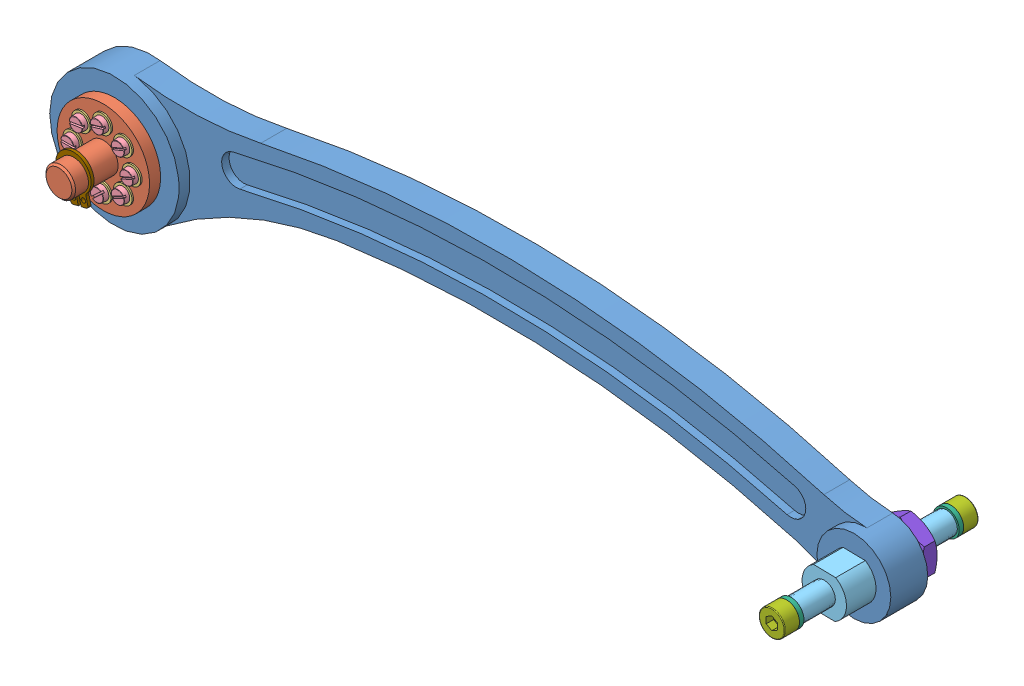
SolidWorks assembly LINK1_SUBASSEMBLY, configuration Default. Lengths in mm.
Overall size (227.5 42.75 52.4).
25 component instances, 9 part files, 49 mates.
Components (placement in the parent):
- link1-1: link1 [Default] at (9.2563 118.8073 156.0715) size (227.5 42.75 10)
- horn-1: horn [Default] at (9.2563 118.8073 166.0715) size (25 25 15)
- plain washer (type a)_is-1: plain washer (type a)_is [IS 2016 A- 2.4] at (3.5994 113.1504 169.4715) x (1 0 0) z (0 -1 0) size (5 0.4 5)
- plain washer (type a)_is-2: plain washer (type a)_is [IS 2016 A- 2.4] at (1.2563 118.8073 169.4715) x (0.987351 0.158553 0) z (0.158553 -0.987351 0) size (5 0.4 5)
- plain washer (type a)_is-4: plain washer (type a)_is [IS 2016 A- 2.4] at (3.5994 124.4641 169.4715) x (0.044015 -0.999031 0) z (-0.999031 -0.044015 0) size (5 0.4 5)
- plain washer (type a)_is-6: plain washer (type a)_is [IS 2016 A- 2.4] at (9.2563 126.8073 169.4715) x (-0.130134 -0.991496 0) z (-0.991496 0.130134 0) size (5 0.4 5)
- plain washer (type a)_is-10: plain washer (type a)_is [IS 2016 A- 2.4] at (14.9131 113.1504 169.4715) x (-0.300328 -0.953836 0) z (-0.953836 0.300328 0) size (5 0.4 5)
- plain washer (type a)_is-12: plain washer (type a)_is [IS 2016 A- 2.4] at (17.2563 118.8073 169.4715) x (-0.461398 -0.887193 0) z (-0.887193 0.461398 0) size (5 0.4 5)
- plain washer (type a)_is-14: plain washer (type a)_is [IS 2016 A- 2.4] at (14.9131 124.4641 169.4715) x (-0.608447 -0.793594 0) z (-0.793594 0.608447 0) size (5 0.4 5)
- plain washer (type a)_is-16: plain washer (type a)_is [IS 2016 A- 2.4] at (9.2563 110.8073 169.4715) x (-0.73701 -0.675882 0) z (-0.675882 0.73701 0) size (5 0.4 5)
- slotted cheese head_is-1: slotted cheese head_is [IS 1336 - M2 x 16 -- 16N] at (1.2563 118.8073 170.8715) x (0 0 -1) z (1 0 0) size (17.4 3.8 3.8)
- slotted cheese head_is-2: slotted cheese head_is [IS 1336 - M2 x 16 -- 16N] at (3.5994 124.4641 170.8715) x (0 0 -1) z (0.987351 0.158553 0) size (17.4 3.8 3.8)
- slotted cheese head_is-4: slotted cheese head_is [IS 1336 - M2 x 16 -- 16N] at (9.2563 126.8073 170.8715) x (0 0 -1) z (0.959125 0.282984 0) size (17.4 3.8 3.8)
- slotted cheese head_is-6: slotted cheese head_is [IS 1336 - M2 x 16 -- 16N] at (14.9131 124.4641 170.8715) x (0 0 -1) z (0.928571 0.371154 0) size (17.4 3.8 3.8)
- slotted cheese head_is-8: slotted cheese head_is [IS 1336 - M2 x 16 -- 16N] at (3.5994 113.1504 170.8715) x (0 0 -1) z (0.906989 0.421154 0) size (17.4 3.8 3.8)
- slotted cheese head_is-10: slotted cheese head_is [IS 1336 - M2 x 16 -- 16N] at (14.9131 113.1504 170.8715) x (0 0 -1) z (0.902849 0.429957 0) size (17.4 3.8 3.8)
- slotted cheese head_is-12: slotted cheese head_is [IS 1336 - M2 x 16 -- 16N] at (17.2563 118.8073 170.8715) x (0 0 -1) z (0.919615 0.39282 0) size (17.4 3.8 3.8)
- slotted cheese head_is-14: slotted cheese head_is [IS 1336 - M2 x 16 -- 16N] at (9.2563 110.8073 170.8715) x (0 0 -1) z (-0.73701 -0.675882 0) size (17.4 3.8 3.8)
- custom_pin-1: custom_pin [Default] at (209.2558 119.2312 150.0715) size (12 10.5 42)
- spring lock washer 6735_is-1: spring lock washer 6735_is [IS 6735- 4] at (209.2558 119.2312 183.0715) x (1 0 0) z (0 -1 0) size (7 1.23 7)
- spring lock washer 6735_is-2: spring lock washer 6735_is [IS 6735- 4] at (209.2558 119.2312 141.0715) x (-0.173648 0.984808 0) z (-0.984808 -0.173648 0) size (7 1.23 7)
- socket head cap screw_is-1: socket head cap screw_is [IS 2269 - M4 x 10-N] at (209.2558 119.2312 188.2715) x (0 0 -1) z (1 0 0) size (14 7 7)
- socket head cap screw_is-2: socket head cap screw_is [IS 2269 - M4 x 10-N] at (209.2558 119.2312 135.8715) x (0 0 1) z (-0.189245 -0.98193 0) size (14 7 7)
- hexagon thin nut (ch)_is-1: hexagon thin nut (ch)_is [IS 1364-4 - M8-N] at (209.2558 119.2312 154.0715) size (13 15.01 4)
- (normal) external_is-1: (normal) external_is [IS 3075 NE- 8] at (9.2563 118.8073 176.2715) x (0.971623 0.236536 0) z (0 0 1) size (9.57 12.08 0.8)
Mates (geometry in assembly coordinates):
- Concentric1: concentric anti-aligned: cylinder of link1-1 through (9.2563 126.8073 166.0715) axis (0 0 1) radius 1.1; cylinder of horn-1 through (9.2563 126.8073 169.0715) axis (0 0 -1) radius 1.1
- Concentric2: concentric aligned: cylinder of link1-1 through (9.2563 118.8073 166.0715) axis (0 0 -1) radius 5; cylinder of horn-1 through (9.2563 118.8073 181.0715) axis (0 0 -1) radius 4.05
- Coincident1: coincident anti-aligned: plane of link1-1 through (159.5579 -23.356 166.0715) normal (0 0 1); plane of horn-1 through (9.2563 118.8073 166.0715) normal (0 0 -1)
- Concentric8: concentric anti-aligned: cylinder of horn-1 through (3.5994 113.1504 169.0715) axis (0 0 -1) radius 1.1; cylinder of plain washer (type a)_is-1 through (3.5994 113.1504 169.4715) axis (0 0 1) radius 1.2
- Coincident5: coincident anti-aligned: plane of horn-1 through (9.2563 118.8073 169.0715) normal (0 0 1); plane of plain washer (type a)_is-1 through (4.7994 113.1504 169.0715) normal (0 0 -1)
- Concentric9: concentric anti-aligned: cylinder of horn-1 through (1.2563 118.8073 169.0715) axis (0 0 -1) radius 1.1; cylinder of plain washer (type a)_is-2 through (1.2563 118.8073 169.4715) axis (0 0 1) radius 1.2
- Coincident6: coincident anti-aligned: plane of horn-1 through (9.2563 118.8073 169.0715) normal (0 0 1); plane of plain washer (type a)_is-2 through (2.4411 118.9976 169.0715) normal (0 0 -1)
- Concentric10: concentric aligned: cylinder of link1-1 through (3.5994 124.4641 166.0715) axis (0 0 1) radius 1.1; cylinder of plain washer (type a)_is-4 through (3.5994 124.4641 169.4715) axis (0 0 1) radius 1.2
- Coincident7: coincident anti-aligned: plane of horn-1 through (9.2563 118.8073 169.0715) normal (0 0 1); plane of plain washer (type a)_is-4 through (3.6522 123.2653 169.0715) normal (0 0 -1)
- Concentric11: concentric aligned: cylinder of link1-1 through (9.2563 126.8073 166.0715) axis (0 0 1) radius 1.1; cylinder of plain washer (type a)_is-6 through (9.2563 126.8073 169.4715) axis (0 0 1) radius 1.2
- Coincident8: coincident anti-aligned: plane of horn-1 through (9.2563 118.8073 169.0715) normal (0 0 1); plane of plain washer (type a)_is-6 through (9.1001 125.6175 169.0715) normal (0 0 -1)
- Concentric12: concentric aligned: cylinder of link1-1 through (14.9131 113.1504 166.0715) axis (0 0 1) radius 1.1; cylinder of plain washer (type a)_is-10 through (14.9131 113.1504 169.4715) axis (0 0 1) radius 1.2
- Coincident9: coincident anti-aligned: plane of horn-1 through (9.2563 118.8073 169.0715) normal (0 0 1); plane of plain washer (type a)_is-10 through (14.5527 112.0058 169.0715) normal (0 0 -1)
- Concentric13: concentric aligned: cylinder of link1-1 through (17.2563 118.8073 166.0715) axis (0 0 1) radius 1.1; cylinder of plain washer (type a)_is-12 through (17.2563 118.8073 169.4715) axis (0 0 1) radius 1.2
- Coincident10: coincident anti-aligned: plane of horn-1 through (9.2563 118.8073 169.0715) normal (0 0 1); plane of plain washer (type a)_is-12 through (16.7026 117.7427 169.0715) normal (0 0 -1)
- Concentric14: concentric aligned: cylinder of link1-1 through (14.9131 124.4641 166.0715) axis (0 0 1) radius 1.1; cylinder of plain washer (type a)_is-14 through (14.9131 124.4641 169.4715) axis (0 0 1) radius 1.2
- Coincident11: coincident anti-aligned: plane of horn-1 through (9.2563 118.8073 169.0715) normal (0 0 1); plane of plain washer (type a)_is-14 through (14.183 123.5118 169.0715) normal (0 0 -1)
- Concentric15: concentric aligned: cylinder of link1-1 through (9.2563 110.8073 166.0715) axis (0 0 1) radius 1.1; cylinder of plain washer (type a)_is-16 through (9.2563 110.8073 169.4715) axis (0 0 1) radius 1.2
- Coincident12: coincident anti-aligned: plane of horn-1 through (9.2563 118.8073 169.0715) normal (0 0 1); plane of plain washer (type a)_is-16 through (8.3719 109.9962 169.0715) normal (0 0 -1)
- Concentric16: concentric anti-aligned: cylinder of horn-1 through (1.2563 118.8073 169.0715) axis (0 0 -1) radius 1.1; cylinder of slotted cheese head_is-1 through (1.2563 118.8073 170.8715) axis (0 0 1) radius 1
- Coincident13: coincident anti-aligned: plane of plain washer (type a)_is-2 through (2.4411 118.9976 169.4715) normal (0 0 1); plane of slotted cheese head_is-1 through (1.2563 120.7073 169.4715) normal (0 0 -1)
- Concentric17: concentric anti-aligned: cylinder of horn-1 through (3.5994 124.4641 169.0715) axis (0 0 -1) radius 1.1; cylinder of slotted cheese head_is-2 through (3.5994 124.4641 170.8715) axis (0 0 1) radius 1
- Coincident14: coincident anti-aligned: plane of plain washer (type a)_is-4 through (3.6522 123.2653 169.4715) normal (0 0 1); plane of slotted cheese head_is-2 through (3.2982 126.3401 169.4715) normal (0 0 -1)
- Concentric18: concentric anti-aligned: cylinder of horn-1 through (9.2563 126.8073 169.0715) axis (0 0 -1) radius 1.1; cylinder of slotted cheese head_is-4 through (9.2563 126.8073 170.8715) axis (0 0 1) radius 1
- Coincident15: coincident anti-aligned: plane of plain washer (type a)_is-6 through (9.1001 125.6175 169.4715) normal (0 0 1); plane of slotted cheese head_is-4 through (8.7186 128.6296 169.4715) normal (0 0 -1)
- Concentric19: concentric anti-aligned: cylinder of horn-1 through (14.9131 124.4641 169.0715) axis (0 0 -1) radius 1.1; cylinder of slotted cheese head_is-6 through (14.9131 124.4641 170.8715) axis (0 0 1) radius 1
- Coincident16: coincident anti-aligned: plane of plain washer (type a)_is-14 through (14.183 123.5118 169.4715) normal (0 0 1); plane of slotted cheese head_is-6 through (14.2079 126.2284 169.4715) normal (0 0 -1)
- Concentric20: concentric anti-aligned: cylinder of horn-1 through (3.5994 113.1504 169.0715) axis (0 0 -1) radius 1.1; cylinder of slotted cheese head_is-8 through (3.5994 113.1504 170.8715) axis (0 0 1) radius 1
- Coincident17: coincident anti-aligned: plane of plain washer (type a)_is-1 through (4.7994 113.1504 169.4715) normal (0 0 1); plane of slotted cheese head_is-8 through (2.7992 114.8737 169.4715) normal (0 0 -1)
- Concentric21: concentric anti-aligned: cylinder of horn-1 through (14.9131 113.1504 169.0715) axis (0 0 -1) radius 1.1; cylinder of slotted cheese head_is-10 through (14.9131 113.1504 170.8715) axis (0 0 1) radius 1
- Coincident18: coincident anti-aligned: plane of plain washer (type a)_is-10 through (14.5527 112.0058 169.4715) normal (0 0 1); plane of slotted cheese head_is-10 through (14.0962 114.8658 169.4715) normal (0 0 -1)
- Concentric22: concentric anti-aligned: cylinder of horn-1 through (17.2563 118.8073 169.0715) axis (0 0 -1) radius 1.1; cylinder of slotted cheese head_is-12 through (17.2563 118.8073 170.8715) axis (0 0 1) radius 1
- Coincident19: coincident anti-aligned: plane of plain washer (type a)_is-12 through (16.7026 117.7427 169.4715) normal (0 0 1); plane of slotted cheese head_is-12 through (16.5099 120.5546 169.4715) normal (0 0 -1)
- Concentric23: concentric aligned: cylinder of link1-1 through (9.2563 110.8073 166.0715) axis (0 0 1) radius 1.1; cylinder of slotted cheese head_is-14 through (9.2563 110.8073 170.8715) axis (0 0 1) radius 1
- Coincident20: coincident anti-aligned: plane of plain washer (type a)_is-16 through (8.3719 109.9962 169.4715) normal (0 0 1); plane of slotted cheese head_is-14 through (10.5405 109.407 169.4715) normal (0 0 -1)
- Concentric24: concentric aligned: cylinder of link1-1 through (209.2558 119.2312 166.0715) axis (0 0 -1) radius 4; cylinder of custom_pin-1 through (209.2558 119.2312 166.0715) axis (0 0 -1) radius 4
- Coincident21: coincident anti-aligned: plane of link1-1 through (159.5579 -23.356 166.0715) normal (0 0 1); plane of custom_pin-1 through (209.2558 119.2312 166.0715) normal (0 0 -1)
- Concentric25: concentric anti-aligned: cylinder of custom_pin-1 through (209.2558 119.2312 183.0715) axis (0 0 1) radius 1.65; cylinder of spring lock washer 6735_is-1 through (209.2558 119.2312 184.2715) axis (0 0 -1) radius 2.2
- Coincident22: coincident anti-aligned: plane of custom_pin-1 through (209.2558 119.2312 183.0715) normal (0 0 1); plane of spring lock washer 6735_is-1 through (209.2558 119.2312 183.0715) normal (0 0 -1)
- Concentric26: concentric anti-aligned: cylinder of custom_pin-1 through (209.2558 119.2312 141.0715) axis (0 0 -1) radius 1.65; cylinder of spring lock washer 6735_is-2 through (209.2558 119.2312 139.8715) axis (0 0 1) radius 2.2
- Coincident23: coincident anti-aligned: plane of custom_pin-1 through (209.2558 119.2312 141.0715) normal (0 0 -1); plane of spring lock washer 6735_is-2 through (209.2558 119.2312 141.0715) normal (0 0 1)
- Concentric27: concentric anti-aligned: cylinder of custom_pin-1 through (209.2558 119.2312 141.0715) axis (0 0 -1) radius 1.65; cylinder of socket head cap screw_is-1 through (209.2558 119.2312 188.2715) axis (0 0 1) radius 2
- Coincident24: coincident anti-aligned: plane of spring lock washer 6735_is-1 through (209.2558 119.2312 184.2715) normal (0 0 1); plane of socket head cap screw_is-1 through (209.2558 122.7312 184.2715) normal (0 0 -1)
- Concentric28: concentric anti-aligned: cylinder of custom_pin-1 through (209.2558 119.2312 141.0715) axis (0 0 1) radius 3; cylinder of socket head cap screw_is-2 through (209.2558 119.2312 135.8715) axis (0 0 -1) radius 2
- Coincident25: coincident anti-aligned: plane of spring lock washer 6735_is-2 through (209.2558 119.2312 139.8715) normal (0 0 -1); plane of socket head cap screw_is-2 through (205.8191 119.8936 139.8715) normal (0 0 1)
- Concentric29: concentric aligned: cylinder of custom_pin-1 through (209.2558 119.2312 141.0715) axis (0 0 1) radius 3; cylinder of hexagon thin nut (ch)_is-1 through (209.2558 119.2312 150.0715) axis (0 0 1) radius 3.4
- Coincident26: coincident aligned: plane of custom_pin-1 through (209.2558 119.2312 150.0715) normal (0 0 -1); plane of hexagon thin nut (ch)_is-1 through (209.2558 126.7368 150.0715) normal (0 0 -1)
- Concentric31: concentric anti-aligned: cylinder of horn-1 through (9.2563 118.8073 181.0715) axis (0 0 1) radius 3.75; cylinder of (normal) external_is-1 through (9.2563 118.8073 177.0715) axis (0 0 -1) radius 3.7
- Coincident27: coincident anti-aligned: plane of horn-1 through (9.2563 122.5573 177.0715) normal (0 0 -1); plane of (normal) external_is-1 through (9.2563 118.8073 177.0715) normal (0 0 1)
